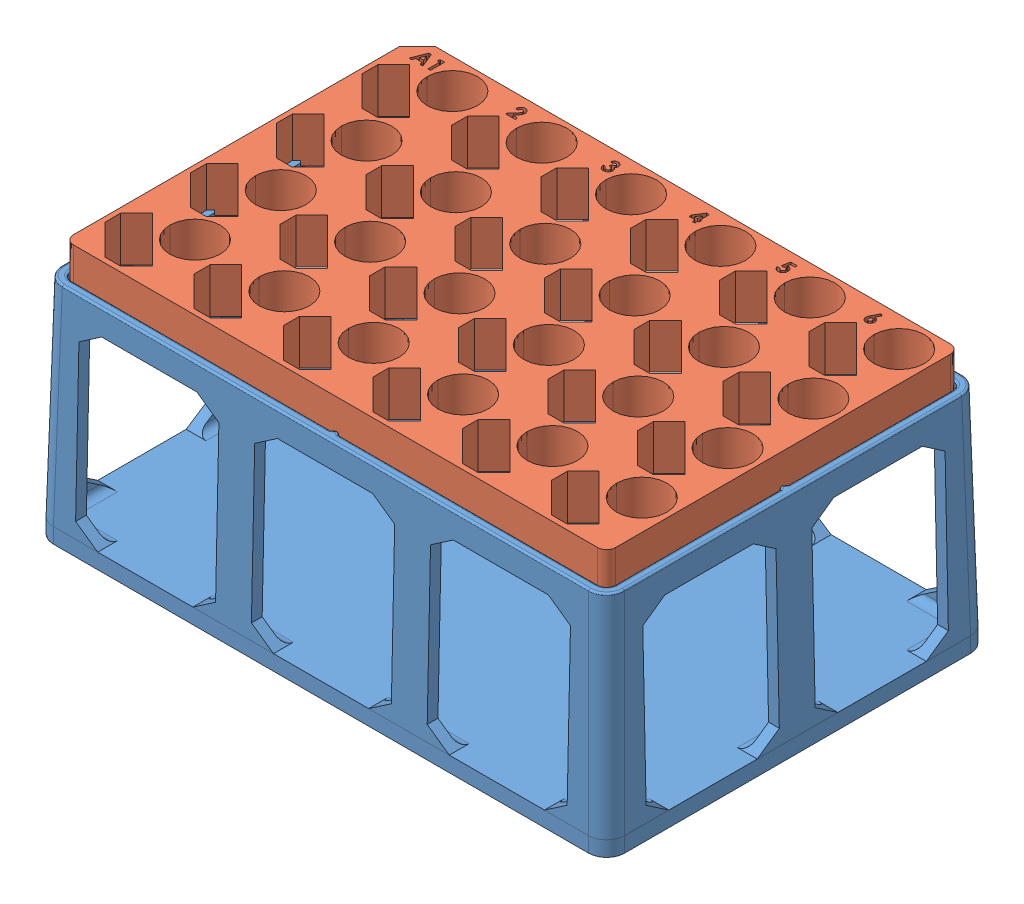
SolidWorks assembly Tubestand, configuration Default. Lengths in mm.
Overall size (127.5 56.6 85.25).
2 component instances, 2 part files, 6 mates.
Components (placement in the parent):
- OpenTrons_Base_Stand_50mm.step-2: OpenTrons_Base_Stand_50mm.step [Default] at (0 -30.0859 0) x (1 0 0) z (0 1 0) size (127.5 85.25 50.01)
- OpenTrons_1.5mL_rack.step-2: OpenTrons_1.5mL_rack.step [Default] at (60.25 21.5986 -39.625) x (1 0 0) z (0 1 0) size (121 78.75 10)
Mates (geometry in assembly coordinates):
- Coincident12: coincident: plane of assembly; plane of OpenTrons_Base_Stand_50mm.step-2 through (0 0 0) normal (0 1 0); point of assembly
- Coincident13: coincident: plane of assembly; plane of OpenTrons_Base_Stand_50mm.step-2 through (0 -30.0859 0) normal (0 0 -1); point of assembly
- Coincident14: coincident: plane of OpenTrons_Base_Stand_50mm.step-2 through (0 -30.0859 0) normal (1 0 0)
- Coincident15: coincident anti-aligned: plane of OpenTrons_Base_Stand_50mm.step-2 through (60.1639 21.5986 39.0399) normal (0 1 0); plane of OpenTrons_1.5mL_rack.step-2 through (60.25 21.5986 -39.625) normal (0 -1 0)
- Coincident16: coincident aligned: line of OpenTrons_Base_Stand_50mm.step-2 through (-60.75 21.5986 -35.7959) axis (0 0 1); line of OpenTrons_1.5mL_rack.step-2 through (-60.75 21.5986 -35.625) axis (0 0 1)
- Coincident19: coincident anti-aligned: plane of OpenTrons_Base_Stand_50mm.step-2 through (58.7504 21.5986 -39.625) normal (0 0 1); plane of OpenTrons_1.5mL_rack.step-2 through (60.25 31.5986 -39.625) normal (0 0 -1)
